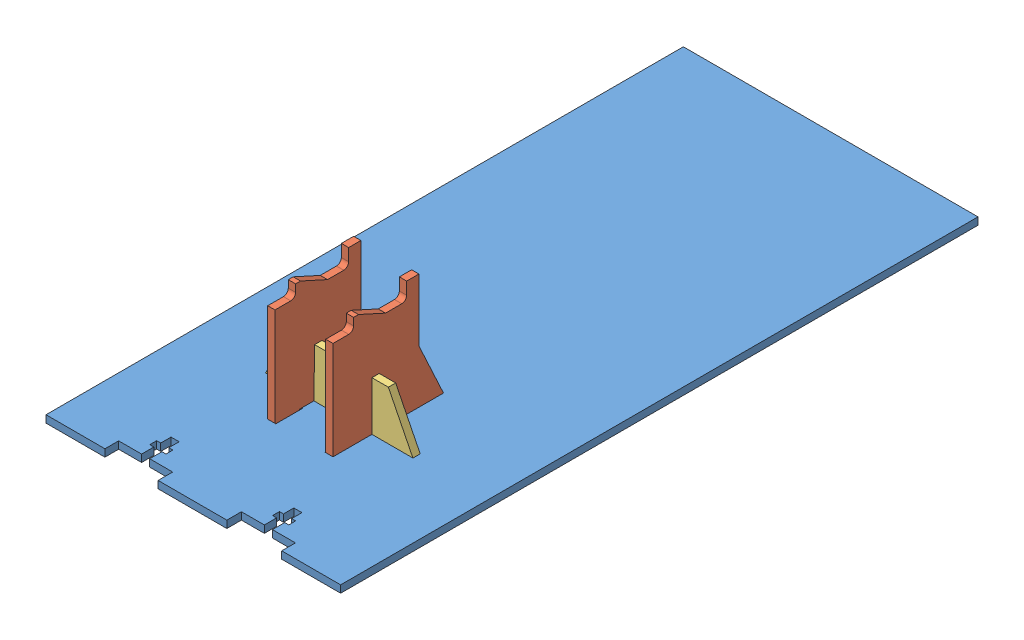
SolidWorks assembly Car, configuration Default. Lengths in mm.
Overall size (120 50.81 259.93).
5 component instances, 3 part files, 3 mates.
Components (placement in the parent):
- chassis-1: chassis [Default] at (141.471 131.4452 174.946) size (120 2.97 259.93)
- PhoneHolderAssembly-1: PhoneHolderAssembly [Default] at (199.1093 129.2776 235.6884) x (0 0 1) z (-1 0 0) size (45 50.81 60)
  - Phone holder-1: Phone holder [Default] at (10.7576 25.1394 44.3363) size (45 50.81 2.97)
  - holdertriangle-1: holdertriangle [Default] at (9.4368 15.1394 57.6383) x (0 0 -1) z (1 0 0) size (60 23.81 2.97)
  - Phone holder-2: Phone holder [Default] at (10.7576 25.1394 67.9685) size (45 50.81 2.97)
Mates (geometry in assembly coordinates):
- Coincident2: coincident anti-aligned: plane of chassis-1 through (128.169 131.4452 263.946) normal (1 0 0); plane of PhoneHolderAssembly-1/Phone holder-2 through (128.169 154.417 246.446) normal (-1 0 0)
- Coincident3: coincident anti-aligned: plane of chassis-1 through (128.169 131.4452 263.946) normal (0 0 -1); plane of PhoneHolderAssembly-1/Phone holder-2 through (128.169 134.417 263.946) normal (0 0 1)
- Coincident4: coincident anti-aligned: plane of chassis-1 through (141.471 134.417 174.946) normal (0 1 0); plane of PhoneHolderAssembly-1/Phone holder-1 through (151.8012 134.417 228.946) normal (0 -1 0)
